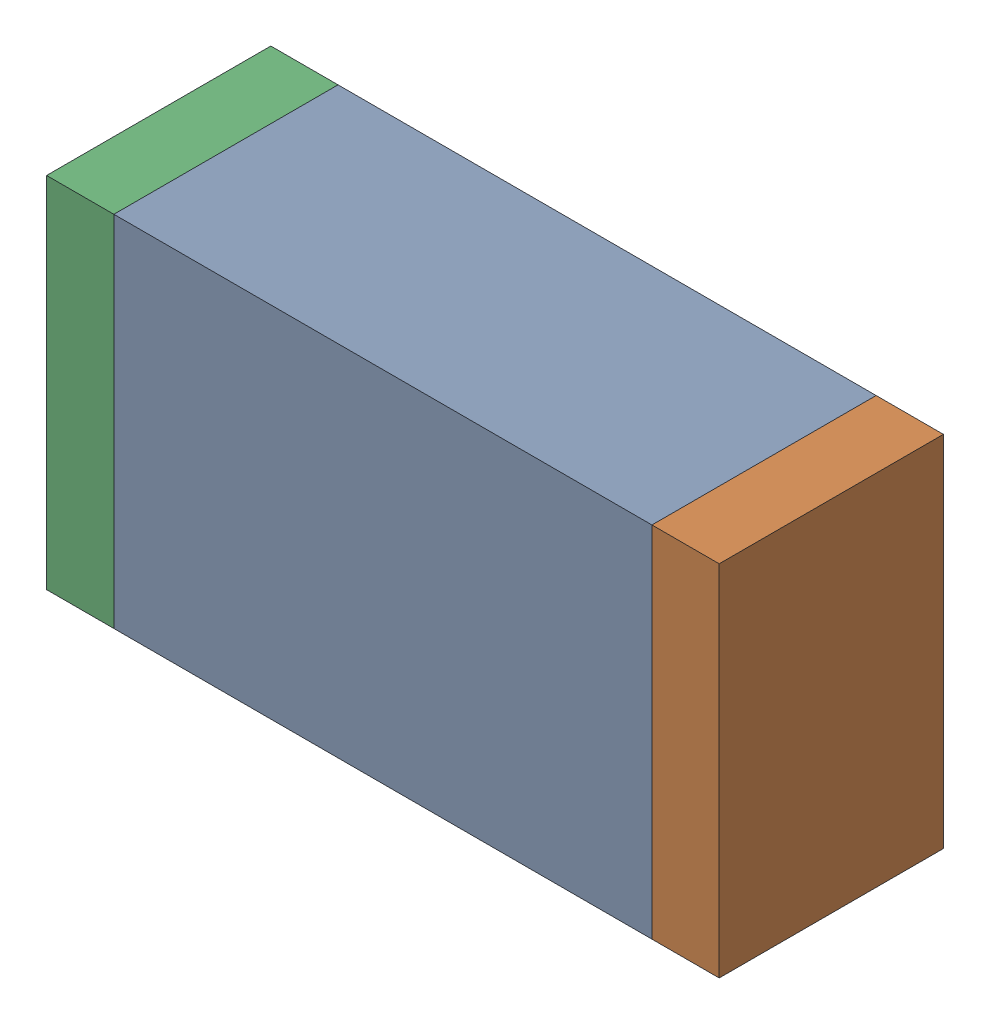
SolidWorks assembly R4, configuration Default. Lengths in mm.
Overall size (1.5 0.8 0.5).
6 component instances, 2 part files, 0 mates.
Components (placement in the parent):
- 836752368-1: 836752368 [Default] at (127.8 30.65 0) size (1.2 0.8 0.5)
  - Extruded-1: Extruded [Default] at origin size (1.2 0.8 0.5)
- 836752496-1: 836752496 [Default] at (128.475 30.65 0) size (0.15 0.8 0.5)
  - Extruded_2-1: Extruded_2 [Default] at origin size (0.15 0.8 0.5)
- 836752496-2: 836752496 [Default] at (127.125 30.65 0) size (0.15 0.8 0.5)
  - Extruded_2-1: Extruded_2 [Default] at origin size (0.15 0.8 0.5)
